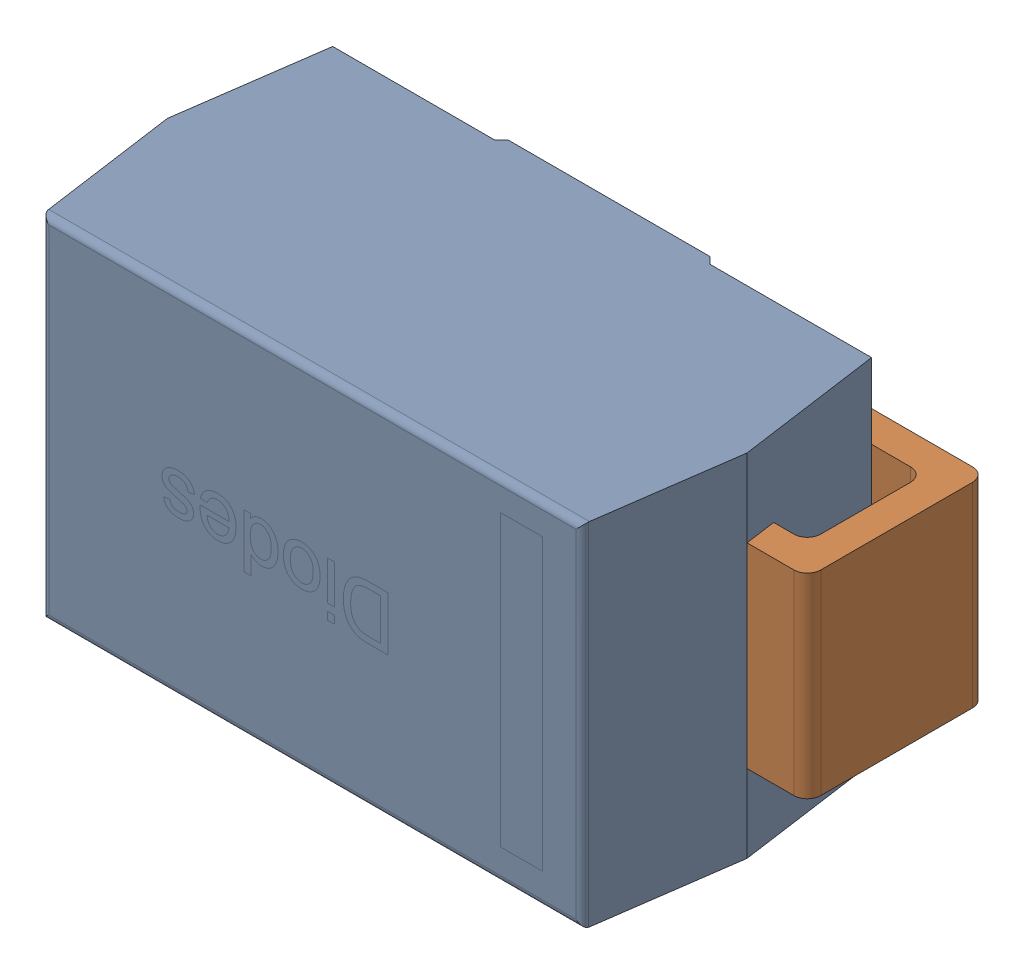
SolidWorks assembly D1, configuration Default. Lengths in mm.
Overall size (5.2 2.61 2.4).
4 component instances, 3 part files, 0 mates.
Components (placement in the parent):
- Diode_Diodes_Inc_SMAJ5_0A-13-F_eec-1: Diode_Diodes_Inc_SMAJ5_0A-13-F_eec [Default] at (1.2604 -1.558 1.2999) x (-1 0 0) z (0 0 1) size (5.2 2.61 2.4)
  - Diodes Inc. SMAJ5.0A-13-F 1-1: Diodes Inc. SMAJ5.0A-13-F 1 [Default] at (-2.4537 -1.5741 -1.1) size (4.3 2.61 2.2)
  - Diodes Inc. SMAJ5.0A-13-F 2-1: Diodes Inc. SMAJ5.0A-13-F 2 [Default] at (-4.8275 -0.8491 -0.6375) x (1 0 0) z (0 -1 0) size (1.14 1.33 1.45)
  - Diodes Inc. SMAJ5.0A-13-F 2_MIR-1: Diodes Inc. SMAJ5.0A-13-F 2_MIR [Default] at (-0.08 -0.8491 -0.6375) x (-1 0 0) z (0 1 0) size (1.14 1.33 1.45)
